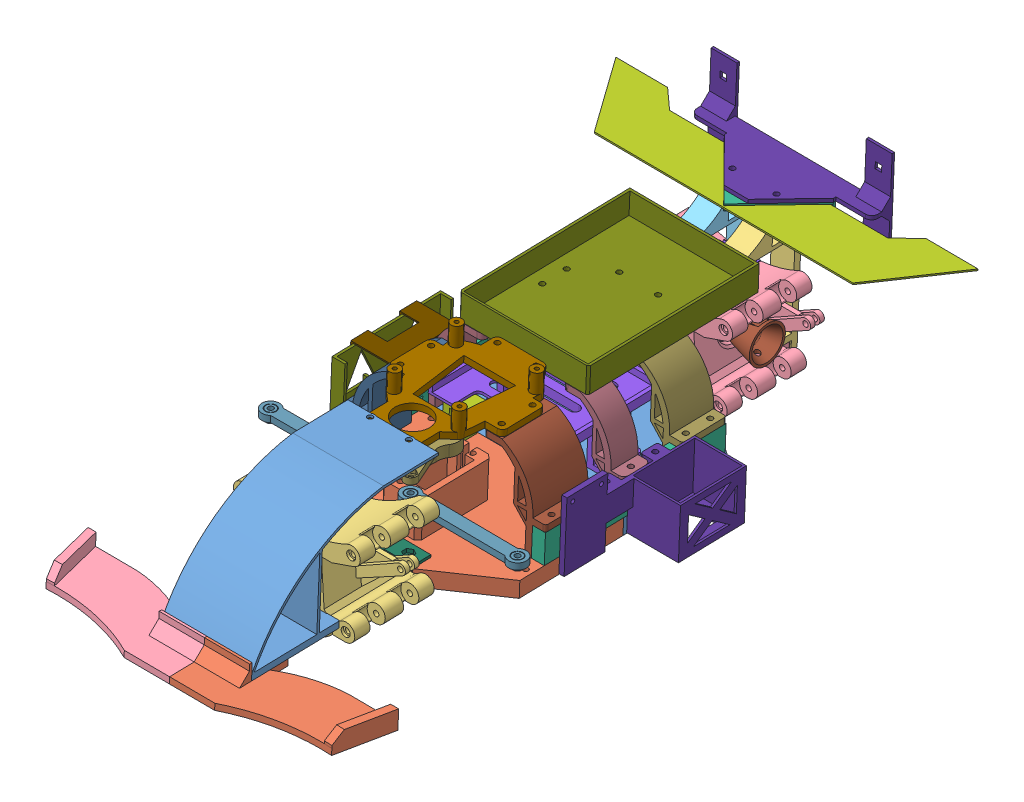
SolidWorks assembly Assem2, configuration Default. Lengths in mm.
Overall size (281.48 151.58 519.86).
44 component instances, 35 part files, 115 mates.
Components (placement in the parent):
- BB_Base-1: BB_Base [Default] at (28.6093 93.0226 121.9081) x (-0.998953 0.035235 0.029162) z (-0.029384 -0.005782 -0.999551) size (160 12.5 120)
- FF_Base-1: FF_Base [Default] at (31.1069 93.5141 206.87) x (0.998953 -0.035235 -0.029162) z (0.029384 0.005782 0.999551) size (160 41.5 120)
- FFDrive_BaseV2-1: FFDrive_BaseV2 [Default] at (33.3841 93.9622 284.3352) x (0.998953 -0.035235 -0.029162) z (0.029384 0.005782 0.999551) size (118.58 68.56 76.42)
- BBDrive_BaseV82-1: BBDrive_BaseV82 [Default] at (24.4221 92.1987 -20.528) x (0.998953 -0.035235 -0.029162) z (0.029384 0.005782 0.999551) size (118.58 68.56 102.04)
- SeizeF-1: SeizeF [Default] at (33.0586 90.9208 276.859) x (-0.998953 0.035235 0.029162) z (-0.029384 -0.005782 -0.999551) size (60 6.8 86)
- Body_sideL-1: Body_sideL [Default] at (-120.6554 114.7973 126.1701) x (-0.998953 0.035235 0.029162) z (0.03505 0.999362 -0.006811) size (10 148 23)
- Body_sideL-2: Body_sideL [Default] at (179.5564 119.2173 117.3192) x (0.998953 -0.035235 -0.029162) z (-0.03505 -0.999362 0.006811) size (10 148 23)
- Pi5_coverF-1: Pi5_coverF [Default] at (31.1961 123.3056 173.9303) x (0.998953 -0.035235 -0.029162) z (0.029384 0.005782 0.999551) size (85 35 25)
- Pi5_coverB-1: Pi5_coverB [Default] at (29.4104 122.9612 114.208) x (0.998953 -0.035235 -0.029162) z (0.029384 0.005782 0.999551) size (95 42 96)
- Lidar-1: Lidar [Default] at (34.5231 195.8195 208.2733) x (-0.029384 -0.005782 -0.999551) z (0.998953 -0.035235 -0.029162) size (114.37 20 89.02)
- LidarArmR-2: LidarArmR [Default] at (-15.6749 -85.014 186.3697) x (0.998559 -0.035298 -0.040412) z (0.040627 0.005385 0.99916) size (48.99 69.85 45)
- LidarArmL-2: LidarArmL [Default] at (64.8691 -87.5454 229.4349) x (-0.998953 0.035235 0.029162) z (-0.029384 -0.005782 -0.999551) size (48.99 69.85 45)
- LidarArmBack-1: LidarArmBack [Default] at (-18.294 -85.6212 83.8021) x (0.998953 -0.035235 -0.029162) z (0.029384 0.005782 0.999551) size (48.99 69.85 36)
- LidarArmBack-2: LidarArmBack [Default] at (61.5781 -88.193 117.4852) x (-0.998953 0.035235 0.029162) z (-0.029384 -0.005782 -0.999551) size (48.99 69.85 36)
- LidarArmMiddle-1: LidarArmMiddle [Default] at (-16.384 -85.2454 148.773) x (0.998953 -0.035235 -0.029162) z (0.029384 0.005782 0.999551) size (48.99 69.85 22)
- LidarArmMiddle-2: LidarArmMiddle [Default] at (62.9003 -87.9328 162.465) x (-0.998953 0.035235 0.029162) z (-0.029384 -0.005782 -0.999551) size (48.99 69.85 22)
- MoterV3-1: MoterV3 [Default] at (-25.1001 106.1781 -59.4629) x (0.998953 -0.035235 -0.029162) z (0.03505 0.999362 -0.006811) size (37.37 43.05 44.5)
- FFBody_to_Drive-1: FFBody_to_Drive [Default] at (-13.9518 104.2128 3.1803) x (0.998953 -0.035235 -0.029162) z (0.029384 0.005782 0.999551) size (60 4 80)
- Battery-1: Battery [Default] at (74.6926 128.1789 305.2934) x (-0.998953 0.035235 0.029162) z (-0.029384 -0.005782 -0.999551) size (44 39 89)
- Radio-2: Radio [Default] at (-13.0755 129.1969 3.01) x (0.998953 -0.035235 -0.029162) z (0.029384 0.005782 0.999551) size (50 55 109.5)
- Battery_Lid-1: Battery_Lid [Default] at (-12.9003 134.1937 2.976) x (0.998953 -0.035235 -0.029162) z (0.029384 0.005782 0.999551) size (46 3 54)
- F1_1-1: F1_1 [Default] at (20.985 -17.6584 2.4568) x (0.998953 -0.035235 -0.029162) z (0.029384 0.005782 0.999551) size (70 82.35 150.07)
- F1_2-2: F1_2 [Default] at (64.4296 96.1923 0.5207) x (0.998953 -0.035235 -0.029162) z (0.029384 0.005782 0.999551) size (120 17.86 60)
- SpoilerTouch2-1: SpoilerTouch2 [Default] at (-4.8903 -16.743 3.6136) x (0.998953 -0.035235 -0.029162) z (0.029384 0.005782 0.999551) size (18 100.35 111.06)
- F1_2_2-1: F1_2_2 [Default] at (64.4296 96.1923 0.5207) x (0.998953 -0.035235 -0.029162) z (0.029384 0.005782 0.999551) size (120 17.86 60)
- SpoilerTouch-5: SpoilerTouch [Default] at (-38.7663 -15.5466 4.8253) x (0.998773 -0.035267 -0.034779) z (0.034997 0.005584 0.999372) size (18 100.35 111.06)
- SpoilerCover-1: SpoilerCover [Default] at (-10.8339 197.6089 2.519) x (0.998969 -0.035232 -0.028617) z (0.028838 0.005801 0.999567) size (84.34 4.8 47)
- Spoiler-4: Spoiler [Default] at (-10.918 195.2105 2.5353) x (0.998969 -0.035232 -0.028617) z (0.028838 0.005801 0.999567) size (140 1.2 60)
- Spoiler-5: Spoiler [Default] at (67.8682 193.6325 0.2714) x (-0.998969 0.035232 0.028617) z (0.028838 0.005801 0.999567) size (140 1.2 60)
- GearRccar52T.step-1: GearRccar52T.step [Default] at (32.7657 128.7205 11.1737) x (-0.029157 0.000668 -0.999575) z (-0.998953 0.035235 0.029162) size (81 81 12.5)
  - Spur Gear (52 teeth).step-1: Spur Gear (52 teeth).step [Default] at origin size (81 81 12.5)
- Driven_axel-1: Driven_axel [Default] at (20.2788 129.161 11.5382) x (-0.035238 -0.999379 0.000398) z (0.029158 -0.00063 0.999575) size (17 42.75 17)
- GearRccar6T.step-1: GearRccar6T.step [Default] at (34.0925 129.4044 55.957) x (0.029157 -0.000668 0.999575) z (-0.998953 0.035235 0.029162) size (12 10.7 15.5)
  - Spur Gear (6 teeth).step-1: Spur Gear (6 teeth).step [Default] at origin size (12 10.7 15.5)
- CoverJoint_in-1: CoverJoint_in [Default] at (72.4741 127.3199 10.0145) x (0.035239 0.999379 -0.000387) z (0.029158 -0.000641 0.999575) size (29.5 27.5 29.5)
- CoverJoint_in-2: CoverJoint_in [Default] at (-19.6793 130.5704 12.7047) x (-0.035239 -0.999379 0.000387) z (0.029158 -0.000641 0.999575) size (29.5 27.5 29.5)
- Servohorn-1: Servohorn [Default] at (33.5475 145.3747 226.672) x (-0.008727 0 0.999962) z (0.008726 0.999962 0.000076) size (55.09 35.31 9)
- Gyro-1: Gyro [Default] at (-42.4215 108.8367 241.4574) x (0.998953 -0.035235 -0.029162) z (0.029384 0.005782 0.999551) size (22.2 9 18.5)
- ServoarmV85-1: ServoarmV85 [Default] at (-24.6411 140.7721 267.1832) x (-0.999924 0.008725 0.008729) z (0.008728 -0.000152 0.999962) size (99 8.2 14)
- ServoarmV85-2: ServoarmV85 [Default] at (90.927 137.5319 267.0158) x (0.999962 -0.008726 0.000049) z (0.00005 0.000076 -1) size (99 8.2 14)
- Supportbody-1: Supportbody [Default] at (89.3094 96.021 140.1153) x (-0.998953 0.035235 0.029162) z (0.029384 0.005782 0.999551) size (20 5 88)
- Supportbody-2: Supportbody [Default] at (-30.565 100.2492 143.6148) x (-0.998953 0.035235 0.029162) z (0.029384 0.005782 0.999551) size (20 5 88)
- BoxBigSize-1: BoxBigSize [Default] at (-11.4334 176.0173 2.6909) x (0.998953 -0.035235 -0.029162) z (0.029384 0.005782 0.999551) size (100 20.13 139.6)
- Futureboard-1: Futureboard [Default] at (-10.7919 198.8082 2.5108) x (0.998969 -0.035232 -0.028617) z (0.028838 0.005801 0.999567) size (140 80 54)
Mates (geometry in assembly coordinates):
- Coincident4: coincident anti-aligned: line of BB_Base-1 through (-49.6201 108.5792 166.6369) axis (0.998953 -0.035235 -0.029162); line of FF_Base-1 through (110.2125 102.9416 161.9709) axis (-0.998953 0.035235 0.029162)
- Coincident5: coincident anti-aligned: plane of BB_Base-1 through (110.2125 102.9416 161.9709) normal (0.029384 0.005782 0.999551); plane of FF_Base-1 through (-49.6201 108.5792 166.6369) normal (-0.029384 -0.005782 -0.999551)
- Coincident6: coincident aligned: line of BB_Base-1 through (110.2125 102.9416 161.9709) axis (-0.03505 -0.999362 0.006811); line of FF_Base-1 through (110.2125 102.9416 161.9709) axis (-0.03505 -0.999362 0.006811)
- Coincident10: coincident aligned: line of BB_Base-1 through (56.8816 95.6016 58.534) axis (-0.998953 0.035235 0.029162); line of BBDrive_BaseV82-1 through (56.8816 95.6016 58.534) axis (-0.998953 0.035235 0.029162)
- Coincident11: coincident aligned: line of BB_Base-1 through (56.8816 95.6016 58.534) axis (-0.03505 -0.999362 0.006811); line of BBDrive_BaseV82-1 through (56.8816 95.6016 58.534) axis (-0.03505 -0.999362 0.006811)
- Concentric3: concentric anti-aligned: cylinder of FF_Base-1 through (13.0376 90.4307 277.4504) axis (0.03505 0.999362 -0.006811) radius 2.1; cylinder of SeizeF-1 through (13.3179 98.4211 277.3959) axis (-0.03505 -0.999362 0.006811) radius 2.1
- Concentric4: concentric anti-aligned: cylinder of FF_Base-1 through (52.9958 89.0213 276.2839) axis (0.03505 0.999362 -0.006811) radius 2.1; cylinder of SeizeF-1 through (53.276 97.0117 276.2294) axis (-0.03505 -0.999362 0.006811) radius 2.1
- Coincident19: coincident anti-aligned: plane of FF_Base-1 through (31.1069 93.5141 206.87) normal (-0.03505 -0.999362 0.006811); plane of SeizeF-1 through (33.1638 93.9188 276.8386) normal (0.03505 0.999362 -0.006811)
- Concentric5: concentric anti-aligned: cylinder of FFDrive_BaseV2-1 through (34.3451 79.7606 334.4115) axis (0.03505 0.999362 -0.006811) radius 2.1; cylinder of SeizeF-1 through (34.9865 98.0489 334.2869) axis (-0.03505 -0.999362 0.006811) radius 2.1
- Concentric6: concentric anti-aligned: cylinder of FFDrive_BaseV2-1 through (33.3167 79.5582 299.4272) axis (0.03505 0.999362 -0.006811) radius 2.1; cylinder of SeizeF-1 through (33.9581 97.8465 299.3026) axis (-0.03505 -0.999362 0.006811) radius 2.1
- Coincident20: coincident anti-aligned: plane of FFDrive_BaseV2-1 through (35.2941 94.3381 349.3061) normal (-0.03505 -0.999362 0.006811); plane of SeizeF-1 through (33.1638 93.9188 276.8386) normal (0.03505 0.999362 -0.006811)
- Coincident21: coincident anti-aligned: plane of FF_Base-1 through (3.8537 107.5113 285.1249) normal (0.029384 0.005782 0.999551); plane of FFDrive_BaseV2-1 through (33.3841 93.9622 284.3352) normal (-0.029384 -0.005782 -0.999551)
- Concentric10: concentric aligned: cylinder of FF_Base-1 through (-12.3648 85.3832 184.9345) axis (0.03505 0.999362 -0.006811) radius 2.1; cylinder of Pi5_coverF-1 through (-12.4699 82.3851 184.9549) axis (0.03505 0.999362 -0.006811) radius 2.1
- Concentric11: concentric aligned: cylinder of FF_Base-1 through (-12.7762 85.3022 170.9408) axis (0.03505 0.999362 -0.006811) radius 2.1; cylinder of Pi5_coverF-1 through (-12.8813 82.3042 170.9612) axis (0.03505 0.999362 -0.006811) radius 2.1
- Coincident28: coincident anti-aligned: plane of FF_Base-1 through (31.545 106.0061 206.7848) normal (0.03505 0.999362 -0.006811); plane of Pi5_coverF-1 through (31.4642 105.9902 204.0361) normal (-0.03505 -0.999362 0.006811)
- Parallel3: parallel aligned: cylinder of BB_Base-1 through (-14.3146 69.127 138.8151) axis (0.03505 0.999362 -0.006811) radius 2.1; cylinder of Pi5_coverB-1 through (-13.1908 101.1669 138.5967) axis (0.03505 0.999362 -0.006811) radius 2.1
- Parallel4: parallel aligned: cylinder of BB_Base-1 through (-14.7847 69.0345 122.8223) axis (0.03505 0.999362 -0.006811) radius 2.1; cylinder of Pi5_coverB-1 through (-13.661 101.0744 122.6039) axis (0.03505 0.999362 -0.006811) radius 2.1
- Coincident29: coincident anti-aligned: plane of BB_Base-1 through (29.0474 105.5146 121.8229) normal (0.03505 0.999362 -0.006811); plane of Pi5_coverB-1 through (29.6786 105.6458 144.3137) normal (-0.03505 -0.999362 0.006811)
- Coincident30: coincident anti-aligned: plane of BB_Base-1 through (29.0474 105.5146 121.8229) normal (0.03505 0.999362 -0.006811); plane of Pi5_coverB-1 through (29.6786 105.6458 144.3137) normal (-0.03505 -0.999362 0.006811)
- Concentric16: concentric aligned: cylinder of BB_Base-1 through (-47.7404 81.9859 91.7018) axis (0.03505 0.999362 -0.006811) radius 2.1; cylinder of Body_sideL-1 through (-47.3899 91.9795 91.6337) axis (0.03505 0.999362 -0.006811) radius 2.1
- Concentric17: concentric aligned: cylinder of FF_Base-1 through (-43.9205 82.7376 221.6435) axis (0.03505 0.999362 -0.006811) radius 2.1; cylinder of Body_sideL-1 through (-43.57 92.7312 221.5754) axis (0.03505 0.999362 -0.006811) radius 2.1
- Coincident32: coincident anti-aligned: plane of FF_Base-1 through (31.545 106.0061 206.7848) normal (0.03505 0.999362 -0.006811); plane of Body_sideL-1 through (-120.7956 110.7999 126.1973) normal (-0.03505 -0.999362 0.006811)
- Concentric18: concentric anti-aligned: cylinder of BB_Base-1 through (102.1026 76.7007 87.3274) axis (0.03505 0.999362 -0.006811) radius 2.1; cylinder of Body_sideL-2 through (104.3809 141.6592 86.8847) axis (-0.03505 -0.999362 0.006811) radius 2.1
- Concentric19: concentric anti-aligned: cylinder of FF_Base-1 through (105.9225 77.4524 217.2691) axis (0.03505 0.999362 -0.006811) radius 2.1; cylinder of Body_sideL-2 through (108.2008 142.4109 216.8264) axis (-0.03505 -0.999362 0.006811) radius 2.1
- Coincident33: coincident anti-aligned: plane of FF_Base-1 through (31.545 106.0061 206.7848) normal (0.03505 0.999362 -0.006811); plane of Body_sideL-2 through (178.8904 100.2294 117.4486) normal (-0.03505 -0.999362 0.006811)
- Concentric33: concentric aligned: cylinder of BB_Base-1 through (-14.7847 69.0345 122.8223) axis (0.03505 0.999362 -0.006811) radius 2.1; cylinder of Pi5_coverB-1 through (-13.661 101.0744 122.6039) axis (0.03505 0.999362 -0.006811) radius 2.1
- Concentric34: concentric aligned: cylinder of BB_Base-1 through (-14.3146 69.127 138.8151) axis (0.03505 0.999362 -0.006811) radius 2.1; cylinder of Pi5_coverB-1 through (-13.1908 101.1669 138.5967) axis (0.03505 0.999362 -0.006811) radius 2.1
- Coincident40: coincident anti-aligned: plane of BB_Base-1 through (29.0474 105.5146 121.8229) normal (0.03505 0.999362 -0.006811); plane of Pi5_coverB-1 through (29.6786 105.6458 144.3137) normal (-0.03505 -0.999362 0.006811)
- Parallel10: parallel aligned: cylinder of BB_Base-1 through (70.1863 66.0374 120.3417) axis (0.03505 0.999362 -0.006811) radius 2.1; cylinder of Pi5_coverB-1 through (71.2501 98.0794 120.1251) axis (0.03505 0.999362 -0.006811) radius 2.1
- Parallel11: parallel aligned: cylinder of BB_Base-1 through (70.6564 66.13 136.3346) axis (0.03505 0.999362 -0.006811) radius 2.1; cylinder of Pi5_coverB-1 through (71.7202 98.1719 136.1179) axis (0.03505 0.999362 -0.006811) radius 2.1
- Coincident41: coincident anti-aligned: plane of BB_Base-1 through (29.0474 105.5146 121.8229) normal (0.03505 0.999362 -0.006811); plane of Pi5_coverB-1 through (29.6786 105.6458 144.3137) normal (-0.03505 -0.999362 0.006811)
- Concentric41: concentric aligned: cylinder of Body_sideL-1 through (-43.57 92.7312 221.5754) axis (0.03505 0.999362 -0.006811) radius 2.1; cylinder of LidarArmR-2 through (-43.6051 91.7319 221.5822) axis (0.03505 0.999362 -0.006811) radius 2.1
- Coincident46: coincident anti-aligned: plane of Body_sideL-1 through (-119.9895 133.7852 126.0407) normal (0.03505 0.999362 -0.006811); plane of LidarArmR-2 through (-6.2964 130.5053 229.8646) normal (-0.03505 -0.999362 0.006811)
- Concentric42: concentric aligned: cylinder of Lidar-1 through (-5.6367 177.1545 199.361) axis (0.03505 0.999362 -0.006811) radius 2.1; cylinder of LidarArmR-2 through (-7.214 132.1832 199.6675) axis (0.03505 0.999362 -0.006811) radius 2.1
- Parallel13: parallel aligned: cylinder of Lidar-1 through (-4.8964 177.3002 224.546) axis (0.03505 0.999362 -0.006811) radius 2.1; cylinder of LidarArmR-2 through (-6.1902 132.3189 224.8463) axis (0.03505 0.999362 -0.006811) radius 2.1
- Concentric44: concentric anti-aligned: cylinder of Body_sideL-2 through (108.2008 142.4109 216.8264) axis (-0.03505 -0.999362 0.006811) radius 2.1; cylinder of LidarArmL-2 through (106.238 86.4466 217.2078) axis (0.03505 0.999362 -0.006811) radius 2.1
- Concentric45: concentric anti-aligned: cylinder of Body_sideL-2 through (107.4662 142.2664 191.8376) axis (-0.03505 -0.999362 0.006811) radius 2.1; cylinder of LidarArmL-2 through (105.5034 86.3021 192.219) axis (0.03505 0.999362 -0.006811) radius 2.1
- Coincident48: coincident anti-aligned: plane of Body_sideL-2 through (179.6966 123.2147 117.2919) normal (0.03505 0.999362 -0.006811); plane of LidarArmL-2 through (71.0971 127.4714 182.9878) normal (-0.03505 -0.999362 0.006811)
- Parallel14: parallel aligned: cylinder of Lidar-1 through (73.4221 174.5378 222.2597) axis (0.03505 0.999362 -0.006811) radius 2.1; cylinder of LidarArmL-2 through (72.0928 129.5605 222.9644) axis (0.03505 0.999362 -0.006811) radius 2.1
- Parallel15: parallel anti-aligned: line of Lidar-1 through (78.7541 174.3565 223.1044) axis (-0.029384 -0.005782 -0.999551); line of LidarArmL-2 through (77.7992 174.1134 182.521) axis (0.029384 0.005782 0.999551)
- Concentric46: concentric aligned: cylinder of Body_sideL-1 through (-46.8022 92.0952 111.6247) axis (0.03505 0.999362 -0.006811) radius 2.1; cylinder of LidarArmBack-1 through (-45.5755 127.0729 111.3863) axis (0.03505 0.999362 -0.006811) radius 2.1
- Concentric47: concentric aligned: cylinder of Body_sideL-1 through (-47.3899 91.9795 91.6337) axis (0.03505 0.999362 -0.006811) radius 2.1; cylinder of LidarArmBack-1 through (-46.1631 126.9572 91.3953) axis (0.03505 0.999362 -0.006811) radius 2.1
- Coincident49: coincident anti-aligned: plane of Body_sideL-1 through (-119.9895 133.7852 126.0407) normal (0.03505 0.999362 -0.006811); plane of LidarArmBack-1 through (-9.4213 129.916 127.3147) normal (-0.03505 -0.999362 0.006811)
- Concentric48: concentric anti-aligned: cylinder of Body_sideL-2 through (104.9686 141.7749 106.8757) axis (-0.03505 -0.999362 0.006811) radius 2.1; cylinder of LidarArmBack-2 through (104.2676 121.7876 107.012) axis (0.03505 0.999362 -0.006811) radius 2.1
- Concentric49: concentric anti-aligned: cylinder of Body_sideL-2 through (104.3809 141.6592 86.8847) axis (-0.03505 -0.999362 0.006811) radius 2.1; cylinder of LidarArmBack-2 through (103.6799 121.672 87.0209) axis (0.03505 0.999362 -0.006811) radius 2.1
- Coincident50: coincident anti-aligned: plane of Body_sideL-2 through (179.6966 123.2147 117.2919) normal (0.03505 0.999362 -0.006811); plane of LidarArmBack-2 through (67.8061 126.8238 71.0381) normal (-0.03505 -0.999362 0.006811)
- Coincident51: coincident aligned: circle of Body_sideL-1; cylinder of LidarArmMiddle-1 through (-44.2532 127.3331 156.3661) axis (0.03505 0.999362 -0.006811) radius 2.1
- Coincident52: coincident aligned: line of Body_sideL-1 through (-46.904 131.9403 231.4511) axis (-0.029384 -0.005782 -0.999551); line of LidarArmMiddle-1 through (-48.9021 131.5472 163.4816) axis (-0.029384 -0.005782 -0.999551)
- Coincident53: coincident anti-aligned: line of Body_sideL-2 through (112.9286 126.3028 226.7851) axis (-0.029384 -0.005782 -0.999551); line of LidarArmMiddle-2 through (110.5191 125.8286 144.8218) axis (0.029384 0.005782 0.999551)
- Concentric50: concentric anti-aligned: cylinder of Body_sideL-2 through (106.2908 142.0351 151.8555) axis (-0.03505 -0.999362 0.006811) radius 2.1; cylinder of LidarArmMiddle-2 through (105.5898 122.0478 151.9918) axis (0.03505 0.999362 -0.006811) radius 2.1
- Concentric55: concentric anti-aligned: cylinder of BB_Base-1 through (-33.6175 69.3783 76.3528) axis (0.03505 0.999362 -0.006811) radius 2.1; cylinder of MoterV3-1 through (-32.1278 111.8512 76.0634) axis (-0.03505 -0.999362 0.006811) radius 2.1
- Concentric56: concentric anti-aligned: cylinder of BB_Base-1 through (-8.6436 68.4974 75.6238) axis (0.03505 0.999362 -0.006811) radius 2.1; cylinder of MoterV3-1 through (-7.154 110.9703 75.3343) axis (-0.03505 -0.999362 0.006811) radius 2.1
- Coincident55: coincident anti-aligned: plane of BB_Base-1 through (29.0474 105.5146 121.8229) normal (0.03505 0.999362 -0.006811); plane of MoterV3-1 through (-25.1001 106.1781 -59.4629) normal (-0.03505 -0.999362 0.006811)
- Coincident57: coincident anti-aligned: plane of FFDrive_BaseV2-1 through (35.6621 104.8314 349.2345) normal (0.03505 0.999362 -0.006811); plane of FFBody_to_Drive-1 through (-13.9518 104.2128 3.1803) normal (-0.03505 -0.999362 0.006811)
- Concentric57: concentric anti-aligned: cylinder of FFDrive_BaseV2-1 through (34.3451 79.7606 334.4115) axis (0.03505 0.999362 -0.006811) radius 2.1; cylinder of FFBody_to_Drive-1 through (35.3616 108.7421 334.214) axis (-0.03505 -0.999362 0.006811) radius 2.1
- Concentric58: concentric anti-aligned: cylinder of FF_Base-1 through (13.0376 90.4307 277.4504) axis (0.03505 0.999362 -0.006811) radius 2.1; cylinder of FFBody_to_Drive-1 through (13.6929 109.1143 277.3231) axis (-0.03505 -0.999362 0.006811) radius 2.1
- Concentric59: concentric anti-aligned: cylinder of FF_Base-1 through (52.9958 89.0213 276.2839) axis (0.03505 0.999362 -0.006811) radius 2.1; cylinder of FFBody_to_Drive-1 through (53.6511 107.7049 276.1566) axis (-0.03505 -0.999362 0.006811) radius 2.1
- Coincident60: coincident anti-aligned: plane of Body_sideL-1 through (-119.9895 133.7852 126.0407) normal (0.03505 0.999362 -0.006811); plane of Battery-1 through (74.6926 128.1789 305.2934) normal (-0.03505 -0.999362 0.006811)
- Concentric64: concentric anti-aligned: cylinder of Body_sideL-1 through (-46.0676 92.2397 136.6135) axis (0.03505 0.999362 -0.006811) radius 2.1; cylinder of Battery-1 through (-44.5254 136.2117 136.3138) axis (-0.03505 -0.999362 0.006811) radius 2.1
- Concentric65: concentric anti-aligned: cylinder of Body_sideL-1 through (-44.8923 92.471 176.5956) axis (0.03505 0.999362 -0.006811) radius 2.1; cylinder of Battery-1 through (-43.3501 136.443 176.2959) axis (-0.03505 -0.999362 0.006811) radius 2.1
- Coincident61: coincident anti-aligned: plane of Body_sideL-2 through (179.6966 123.2147 117.2919) normal (0.03505 0.999362 -0.006811); plane of Radio-2 through (-13.0755 129.1969 3.01) normal (-0.03505 -0.999362 0.006811)
- Concentric66: concentric aligned: cylinder of Body_sideL-2 through (105.7032 141.9194 131.8645) axis (-0.03505 -0.999362 0.006811) radius 2.1; cylinder of Radio-2 through (105.3176 130.9265 131.9394) axis (-0.03505 -0.999362 0.006811) radius 2.1
- Concentric67: concentric aligned: cylinder of Body_sideL-2 through (106.8785 142.1507 171.8466) axis (-0.03505 -0.999362 0.006811) radius 2.1; cylinder of Radio-2 through (106.493 131.1577 171.9215) axis (-0.03505 -0.999362 0.006811) radius 2.1
- Coincident62: coincident anti-aligned: plane of Battery-1 through (74.8678 133.1757 305.2593) normal (0.03505 0.999362 -0.006811); plane of Battery_Lid-1 through (-12.9003 134.1937 2.976) normal (-0.03505 -0.999362 0.006811)
- Concentric68: concentric aligned: cylinder of Battery-1 through (-43.3501 136.443 176.2959) axis (-0.03505 -0.999362 0.006811) radius 2.1; cylinder of Battery_Lid-1 through (-43.315 137.4423 176.2891) axis (-0.03505 -0.999362 0.006811) radius 2.1
- Concentric69: concentric anti-aligned: cylinder of Body_sideL-1 through (-46.0676 92.2397 136.6135) axis (0.03505 0.999362 -0.006811) radius 2.1; cylinder of Battery_Lid-1 through (-44.4904 137.211 136.307) axis (-0.03505 -0.999362 0.006811) radius 2.1
- Coincident69: coincident anti-aligned: plane of Lidar-1 through (33.9974 180.8291 208.3755) normal (0.03505 0.999362 -0.006811); plane of F1_1-1 through (-7.0589 180.8633 2.1328) normal (-0.03505 -0.999362 0.006811)
- Concentric79: concentric aligned: cylinder of Lidar-1 through (20.7606 176.7391 274.2534) axis (0.03505 0.999362 -0.006811) radius 2.1; cylinder of F1_1-1 through (19.7792 148.757 274.4441) axis (0.03505 0.999362 -0.006811) radius 2.1
- Concentric80: concentric aligned: cylinder of Lidar-1 through (50.7292 175.6821 273.3785) axis (0.03505 0.999362 -0.006811) radius 2.1; cylinder of F1_1-1 through (49.7478 147.6999 273.5692) axis (0.03505 0.999362 -0.006811) radius 2.1
- Parallel17: parallel aligned: cylinder of FFDrive_BaseV2-1 through (55.3149 90.6642 353.741) axis (0.03505 0.999362 -0.006811) radius 2.1; cylinder of F1_1-1 through (54.3694 70.6828 353.4829) axis (0.03505 0.999362 -0.006811) radius 2.1
- Parallel18: parallel aligned: cylinder of FFDrive_BaseV2-1 through (15.3568 92.0736 354.9075) axis (0.03505 0.999362 -0.006811) radius 2.1; cylinder of F1_1-1 through (14.4113 72.0922 354.6494) axis (0.03505 0.999362 -0.006811) radius 2.1
- Concentric81: concentric aligned: cylinder of F1_1-1 through (47.4851 116.3071 405.4447) axis (-0.03505 -0.999362 0.006811) radius 2.1; cylinder of F1_2-2 through (46.9593 101.3167 405.5468) axis (-0.03505 -0.999362 0.006811) radius 2.1
- Coincident71: coincident anti-aligned: plane of F1_1-1 through (-9.8753 100.5642 2.6801) normal (-0.03505 -0.999362 0.006811); plane of F1_2-2 through (0.9195 102.7892 384.6716) normal (0.03505 0.999362 -0.006811)
- Coincident75: coincident anti-aligned: plane of Lidar-1 through (33.8221 175.8322 208.4096) normal (-0.03505 -0.999362 0.006811); plane of LidarArmR-2 through (-4.6542 177.3258 229.5455) normal (0.03505 0.999362 -0.006811)
- Coincident76: coincident anti-aligned: plane of FFDrive_BaseV2-1 through (5.8647 102.4485 360.1288) normal (0.03505 0.999362 -0.006811); plane of F1_1-1 through (-9.8753 100.5642 2.6801) normal (-0.03505 -0.999362 0.006811)
- Parallel21: parallel aligned: cylinder of Lidar-1 through (72.6817 174.3921 197.0746) axis (0.03505 0.999362 -0.006811) radius 2.1; cylinder of LidarArmL-2 through (71.3523 129.4148 197.7757) axis (0.03505 0.999362 -0.006811) radius 2.1
- Concentric86: concentric aligned: cylinder of Lidar-1 through (-5.6367 177.1545 199.361) axis (0.03505 0.999362 -0.006811) radius 2.1; cylinder of LidarArmR-2 through (-7.214 132.1832 199.6675) axis (0.03505 0.999362 -0.006811) radius 2.1
- Concentric90: concentric aligned: cylinder of F1_1-1 through (12.5217 117.5404 406.4653) axis (-0.03505 -0.999362 0.006811) radius 2.1; cylinder of F1_2_2-1 through (11.996 102.5499 406.5675) axis (-0.03505 -0.999362 0.006811) radius 2.1
- Coincident81: coincident anti-aligned: circle of F1_1-1; cylinder of F1_2_2-1 through (26.9803 102.0214 406.1301) axis (-0.03505 -0.999362 0.006811) radius 2.1
- Coincident82: coincident anti-aligned: plane of F1_1-1 through (-9.8753 100.5642 2.6801) normal (-0.03505 -0.999362 0.006811); plane of F1_2_2-1 through (0.9195 102.7892 384.6716) normal (0.03505 0.999362 -0.006811)
- Coincident90: coincident anti-aligned: plane of BBDrive_BaseV82-1 through (32.3652 98.8545 -30.8045) normal (0.03505 0.999362 -0.006811); plane of SpoilerTouch-5 through (17.273 99.6089 2.2194) normal (-0.03505 -0.999362 0.006811)
- Coincident95: coincident anti-aligned: circle of SpoilerTouch-5; circle of SpoilerCover-1
- Concentric93: concentric aligned: cylinder of SpoilerTouch2-1 through (44.3009 180.8809 -24.6267) axis (0.03505 0.999362 -0.006811) radius 2.1; cylinder of SpoilerCover-1 through (44.6864 191.8739 -24.7017) axis (0.03505 0.999362 -0.006811) radius 2.1
- Concentric94: concentric aligned: cylinder of SpoilerCover-1 through (10.8269 197.8709 -23.7596) axis (-0.03505 -0.999362 0.006811) radius 2.1; cylinder of Spoiler-4 through (10.7428 195.4724 -23.7432) axis (-0.03505 -0.999362 0.006811) radius 2.1
- Coincident100: coincident anti-aligned: plane of SpoilerCover-1 through (-10.918 195.2105 2.5353) normal (0.03505 0.999362 -0.006811); plane of Spoiler-5 through (67.8262 192.4333 0.2796) normal (-0.03505 -0.999362 0.006811)
- Coincident101: coincident anti-aligned: circle of SpoilerCover-1; cylinder of Spoiler-5 through (44.7285 193.0731 -24.7098) axis (0.03505 0.999362 -0.006811) radius 2.1
- Coincident102: coincident anti-aligned: plane of SpoilerCover-1 through (-14.9884 195.0428 -43.0063) normal (0.028838 0.005801 0.999567); plane of Spoiler-5 through (32.5186 346.9747 -45.2587) normal (-0.028838 -0.005801 -0.999567)
- Coincident103: coincident anti-aligned: plane of SpoilerCover-1 through (-14.9884 195.0428 -43.0063) normal (0.028838 0.005801 0.999567); plane of Spoiler-4 through (21.7991 41.3388 -43.1756) normal (-0.028838 -0.005801 -0.999567)
- Coincident104: coincident anti-aligned: plane of SpoilerCover-1 through (-10.918 195.2105 2.5353) normal (0.03505 0.999362 -0.006811); plane of Spoiler-4 through (-10.918 195.2105 2.5353) normal (-0.03505 -0.999362 0.006811)
- Coincident107: coincident anti-aligned: plane of GearRccar52T.step-1/Spur Gear (52 teeth).step-1 through (20.2788 129.161 11.5382) normal (-0.998953 0.035235 0.029162); plane of Driven_axel-1 through (20.2788 129.161 11.5382) normal (0.998953 -0.035235 -0.029162)
- Concentric95: concentric aligned: cylinder of GearRccar52T.step-1/Spur Gear (52 teeth).step-1 through (32.7657 128.7205 11.1737) axis (-0.998953 0.035235 0.029162) radius 7.5; cylinder of Driven_axel-1 through (66.4436 127.5327 10.1905) axis (-0.998953 0.035235 0.029162) radius 7.5
- Coincident108: coincident anti-aligned: circle of GearRccar52T.step-1/Spur Gear (52 teeth).step-1; cylinder of Driven_axel-1 through (66.4436 127.5327 10.1905) axis (-0.998953 0.035235 0.029162) radius 7.5
- Concentric97: concentric aligned: cylinder of MoterV3-1 through (-25.9635 131.5227 57.7102) axis (0.998953 -0.035235 -0.029162) radius 2.5; cylinder of GearRccar6T.step-1/Spur Gear (6 teeth).step-1 through (18.6088 129.9505 56.409) axis (0.998953 -0.035235 -0.029162) radius 1.6435
- Concentric98: concentric aligned: cylinder of Driven_axel-1 through (47.75 128.192 10.7362) axis (-0.998953 0.035235 0.029162) radius 2.5; circle of CoverJoint_in-1
- Concentric99: concentric anti-aligned: cylinder of Driven_axel-1 through (47.75 128.192 10.7362) axis (-0.998953 0.035235 0.029162) radius 2.5; cylinder of CoverJoint_in-2 through (-29.9186 130.9315 13.0036) axis (0.998953 -0.035235 -0.029162) radius 2.1
- Coincident109: coincident anti-aligned: plane of Driven_axel-1 through (5.0448 129.6983 11.9829) normal (-0.998953 0.035235 0.029162); plane of CoverJoint_in-2 through (5.0448 129.6983 11.9829) normal (0.998953 -0.035235 -0.029162)
- Coincident110: coincident anti-aligned: plane of Driven_axel-1 through (47.8228 130.2574 10.7354) normal (0.998953 -0.035235 -0.029162); plane of CoverJoint_in-1 through (47.75 128.192 10.7362) normal (-0.998953 0.035235 0.029162)
- Concentric100: concentric anti-aligned: cylinder of FF_Base-1 through (-43.3328 82.8532 241.6345) axis (0.03505 0.999362 -0.006811) radius 2.1; cylinder of Gyro-1 through (-42.3514 110.8354 241.4438) axis (-0.03505 -0.999362 0.006811) radius 2.1
- Coincident111: coincident anti-aligned: plane of FF_Base-1 through (31.545 106.0061 206.7848) normal (0.03505 0.999362 -0.006811); plane of Gyro-1 through (-42.4215 108.8367 241.4574) normal (-0.03505 -0.999362 0.006811)
- Coincident112: coincident anti-aligned: line of FF_Base-1 through (-49.6201 108.5792 166.6369) axis (0.029384 0.005782 0.999551); line of Gyro-1 through (-47.2106 109.0533 248.6001) axis (-0.029384 -0.005782 -0.999551)
- Concentric101: concentric anti-aligned: cylinder of Servohorn-1 through (20.4349 149.4862 266.7911) axis (0.008726 0.999962 0.000076) radius 2.1427; cylinder of ServoarmV85-1 through (20.4017 145.6792 266.7908) axis (-0.008726 -0.999962 -0.000076) radius 2.1
- Concentric102: concentric anti-aligned: cylinder of Servohorn-1 through (46.0277 149.2629 267.0145) axis (0.008726 0.999962 0.000076) radius 2.1427; cylinder of ServoarmV85-2 through (45.975 143.2244 267.014) axis (-0.008726 -0.999962 -0.000076) radius 2.1
- Concentric103: concentric anti-aligned: cylinder of FF_Base-1 through (91.7644 117.3458 198.446) axis (-0.03505 -0.999362 0.006811) radius 2.1; cylinder of Supportbody-1 through (90.8531 91.3624 198.6231) axis (0.03505 0.999362 -0.006811) radius 2.1
- Concentric104: concentric anti-aligned: cylinder of BB_Base-1 through (89.6488 116.9295 126.4783) axis (-0.03505 -0.999362 0.006811) radius 2.1; cylinder of Supportbody-1 through (88.7375 90.9461 126.6554) axis (0.03505 0.999362 -0.006811) radius 2.1
- Coincident113: coincident anti-aligned: plane of BB_Base-1 through (28.7845 98.0194 121.874) normal (-0.03505 -0.999362 0.006811); plane of Supportbody-1 through (89.3094 96.021 140.1153) normal (0.03505 0.999362 -0.006811)
- Concentric105: concentric anti-aligned: cylinder of FF_Base-1 through (-28.11 121.574 201.9455) axis (-0.03505 -0.999362 0.006811) radius 2.1; cylinder of Supportbody-2 through (-29.0213 95.5906 202.1226) axis (0.03505 0.999362 -0.006811) radius 2.1
- Concentric106: concentric anti-aligned: cylinder of BB_Base-1 through (-30.2256 121.1577 129.9778) axis (-0.03505 -0.999362 0.006811) radius 2.1; cylinder of Supportbody-2 through (-31.137 95.1743 130.1549) axis (0.03505 0.999362 -0.006811) radius 2.1
- Coincident114: coincident anti-aligned: plane of BB_Base-1 through (28.7845 98.0194 121.874) normal (-0.03505 -0.999362 0.006811); plane of Supportbody-2 through (-30.565 100.2492 143.6148) normal (0.03505 0.999362 -0.006811)
- Coincident115: coincident aligned: circle of LidarArmMiddle-1; circle of BoxBigSize-1
- Coincident116: coincident anti-aligned: circle of LidarArmBack-1; cylinder of BoxBigSize-1 through (-7.0782 179.4612 89.9426) axis (-0.03505 -0.999362 0.006811) radius 2.1
- Concentric107: concentric aligned: cylinder of BBDrive_BaseV82-1 through (44.002 88.4721 -26.0843) axis (0.03505 0.999362 -0.006811) radius 2.1; cylinder of SpoilerTouch2-1 through (44.1773 93.469 -26.1183) axis (0.03505 0.999362 -0.006811) radius 2.1
- Coincident117: coincident anti-aligned: plane of BBDrive_BaseV82-1 through (24.1282 92.1408 -30.5235) normal (-0.029384 -0.005782 -0.999551); plane of SpoilerTouch2-1 through (46.0962 -18.7639 -30.5277) normal (0.029384 0.005782 0.999551)
- Concentric108: concentric aligned: cylinder of SpoilerCover-1 through (10.8269 197.8709 -23.7596) axis (-0.03505 -0.999362 0.006811) radius 2.1; cylinder of Futureboard-1 through (10.869 199.0701 -23.7678) axis (-0.03505 -0.999362 0.006811) radius 2.1
- Concentric109: concentric aligned: cylinder of SpoilerCover-1 through (44.8547 196.6708 -24.7343) axis (-0.03505 -0.999362 0.006811) radius 2.1; cylinder of Futureboard-1 through (44.8967 197.87 -24.7425) axis (-0.03505 -0.999362 0.006811) radius 2.1
- Coincident118: coincident anti-aligned: plane of SpoilerCover-1 through (-10.7919 198.8082 2.5108) normal (0.03505 0.999362 -0.006811); plane of Futureboard-1 through (-10.7919 198.8082 2.5108) normal (-0.03505 -0.999362 0.006811)
